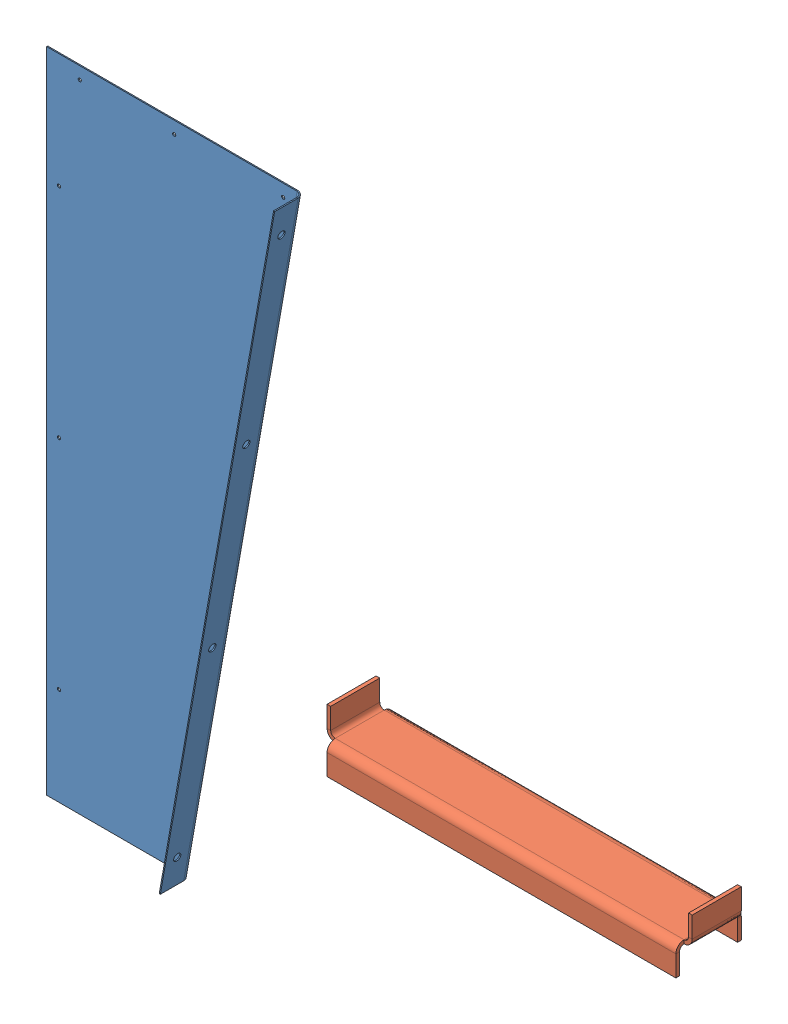
SolidWorks assembly Assem1, configuration Default. Lengths in mm.
Overall size (1013.59 1134.87 263.41).
2 component instances, 2 part files, 0 mates.
Components (placement in the parent):
- 4701 A11 hood side-1: 4701 A11 hood side [Default] at (-185.3069 1031.4687 1136.1965) size (447.26 1134.87 50.8)
- Part1-1: Part1 [Default] at (512.6657 122.1392 978.8424) size (638.18 95.25 114.3)
